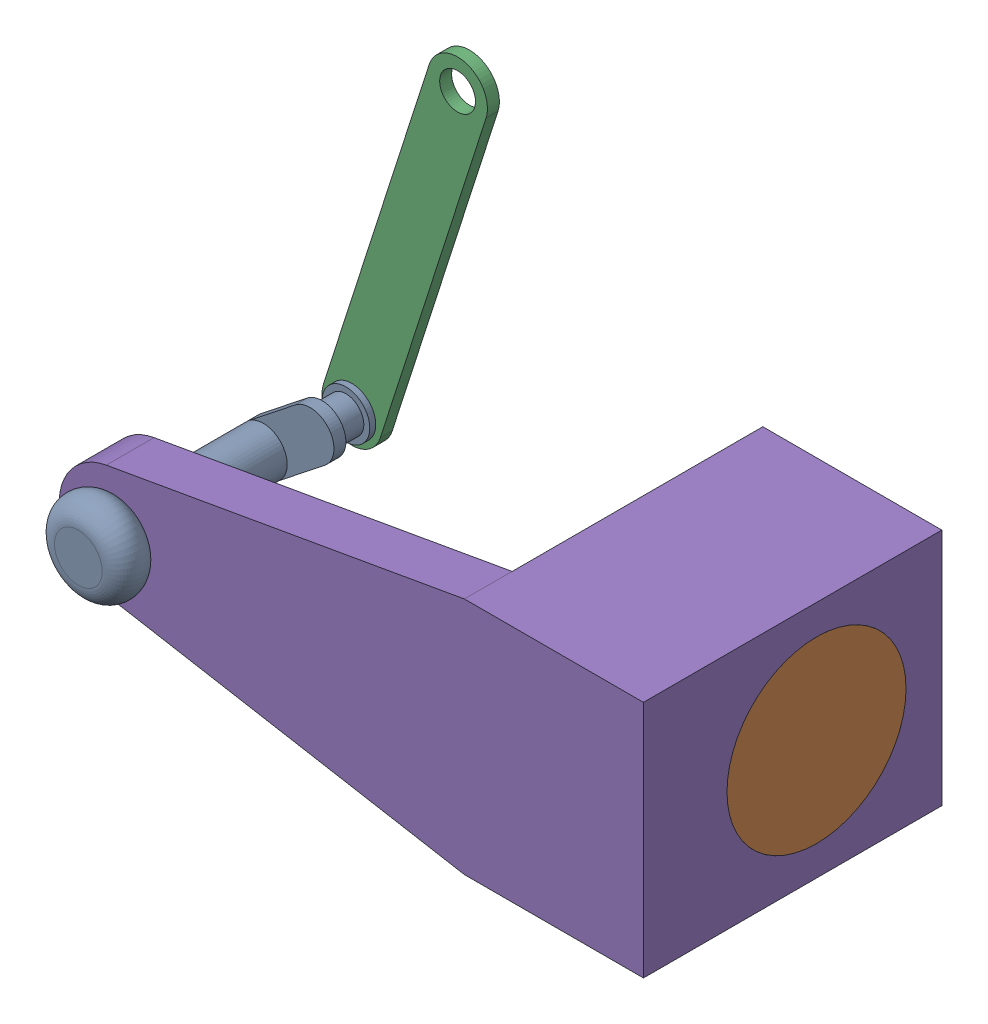
SolidWorks assembly Assem1, configuration Default. Lengths in mm.
Overall size (246.75 219.33 140.88).
5 component instances, 5 part files, 12 mates.
Components (placement in the parent):
- Arm-1: Arm [Default] at (-165.8859 65.5368 -61.6176) x (-0.621474 0.783435 0) z (0 0 -1) size (36.88 53.44 102.5)
- Cylinder-1: Cylinder [Default] at (35.3755 50 -72.5) x (-1 0 0) z (0 0.013712 0.999906) size (75 75 75)
- Link-1: Link [Default] at (-165.8859 65.5368 -81.6176) x (0.305441 0.952211 0) z (0 0 1) size (170 25 5)
- Pin-1: Pin [Default] at (-2.1245 50 -72.5) x (1 0 0) z (0 -0.013712 -0.999906) size (15 15 75)
- Base-2: Base [Default] at (-185.4718 50 0) x (1 0 0) z (0 -1 0) size (244.76 125 100)
Mates (geometry in assembly coordinates):
- Coincident1: coincident aligned: plane of Base-2 through (-185.4718 50 0) normal (0 0 1)
- Coincident2: coincident anti-aligned: plane of Base-2 through (-39.6245 0 -125) normal (0 -1 0)
- Concentric5: concentric aligned: cylinder of Pin-1 through (-2.1245 49.4858 -109.9965) axis (0 0.013712 0.999906) radius 7.5; cylinder of Cylinder-1 through (-2.1245 49.4858 -109.9965) axis (0 0.013712 0.999906) radius 7.5
- Concentric7: concentric aligned: cylinder of Pin-1 through (-9.6245 50 -72.5) axis (1 0 0) radius 37.5; cylinder of Cylinder-1 through (-39.6245 50 -72.5) axis (1 0 0) radius 37.5
- Concentric11: concentric anti-aligned: cylinder of Cylinder-1 through (6.3944 50 -72.5) axis (1 0 0) radius 37.5; cylinder of Base-2 through (81.3944 50 -72.5) axis (-1 0 0) radius 37.5
- Coincident11: coincident aligned: circle of Cylinder-1; plane of Base-2 through (-39.6245 100 197.0254) normal (-1 0 0)
- Concentric13: concentric aligned: cylinder of Arm-1 through (-185.4718 50 -66.6176) axis (0 0 1) radius 10; cylinder of Base-2 through (-185.4718 50 -125) axis (0 0 1) radius 10
- Coincident12: coincident anti-aligned: circle of Arm-1; plane of Base-2 through (-185.4718 50 0) normal (0 0 1)
- Concentric14: concentric anti-aligned: cylinder of Arm-1 through (-165.8859 65.5368 -86.6176) axis (0 0 1) radius 7.5; cylinder of Link-1 through (-165.8859 65.5368 -79.1176) axis (0 0 -1) radius 7.5
- Coincident14: coincident anti-aligned: circle of Arm-1; plane of Link-1 through (-165.8859 65.5368 -79.1176) normal (0 0 1)
- Concentric20: concentric aligned: cylinder of Cylinder-1 through (-2.1245 49.4858 -109.9965) axis (0 0.013712 0.999906) radius 7.5; cylinder of Pin-1 through (-2.1245 49.4858 -109.9965) axis (0 0.013712 0.999906) radius 7.5
- Concentric22: concentric anti-aligned: cylinder of Cylinder-1 through (-39.6245 50 -72.5) axis (1 0 0) radius 37.5; cylinder of Base-2 through (35.3755 50 -72.5) axis (-1 0 0) radius 37.5
